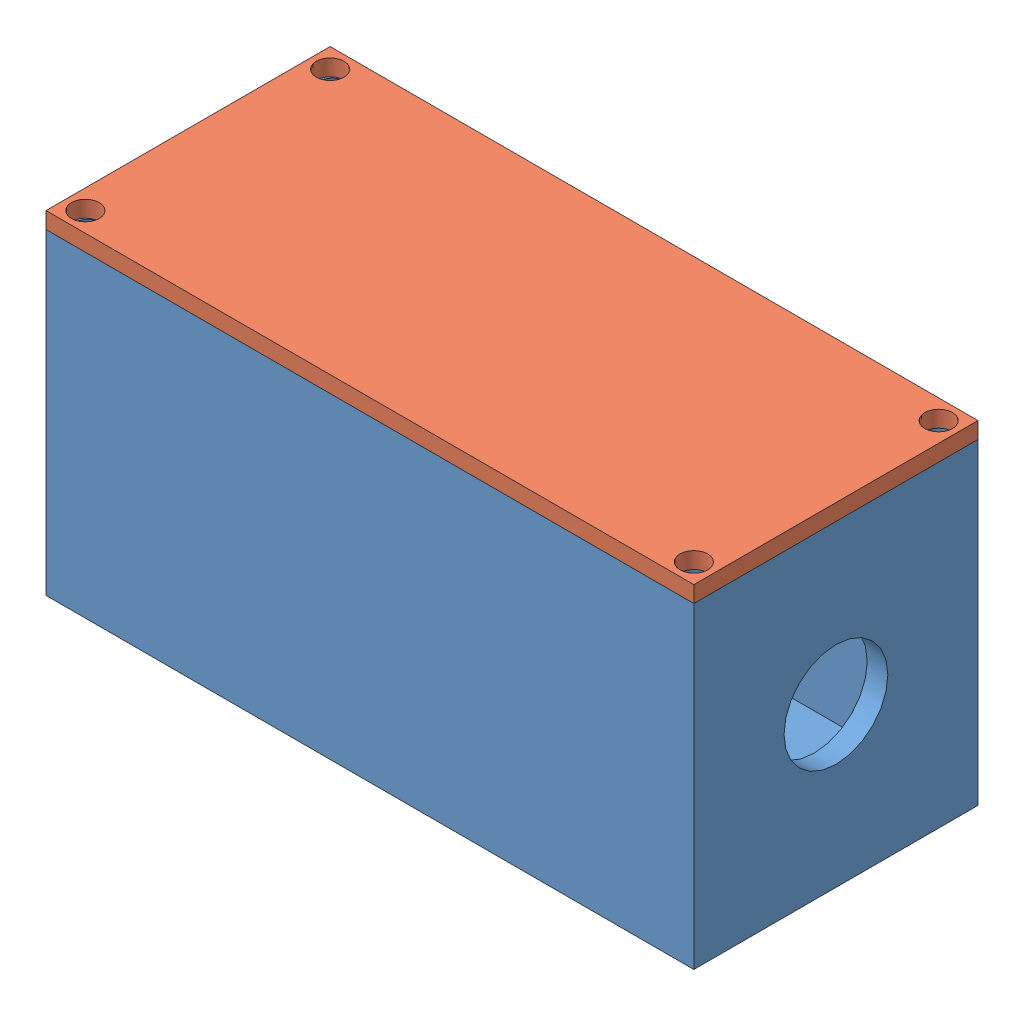
SolidWorks assembly AssemblyV2, configuration Default. Lengths in mm.
Overall size (59.28 30.5 26).
2 component instances, 2 part files, 3 mates.
Components (placement in the parent):
- BDv2-1: BDv2 [Default] at origin size (59.28 29 26)
- CapuchonV2-2: CapuchonV2 [Default] at (0 29 0) size (59.28 1.5 26)
Mates (geometry in assembly coordinates):
- Coincident1: coincident: plane of BDv2-1 through (0 29 0) normal (0 1 0); plane of CapuchonV2-2 through (0 29 0) normal (0 -1 0)
- Coincident2: coincident: plane of BDv2-1 through (0 29 -26) normal (0 0 -1); plane of CapuchonV2-2 through (0 30.5 -26) normal (0 0 -1)
- Coincident3: coincident: plane of BDv2-1 through (0 29 0) normal (-1 0 0); plane of CapuchonV2-2 through (0 30.5 0) normal (-1 0 0)
